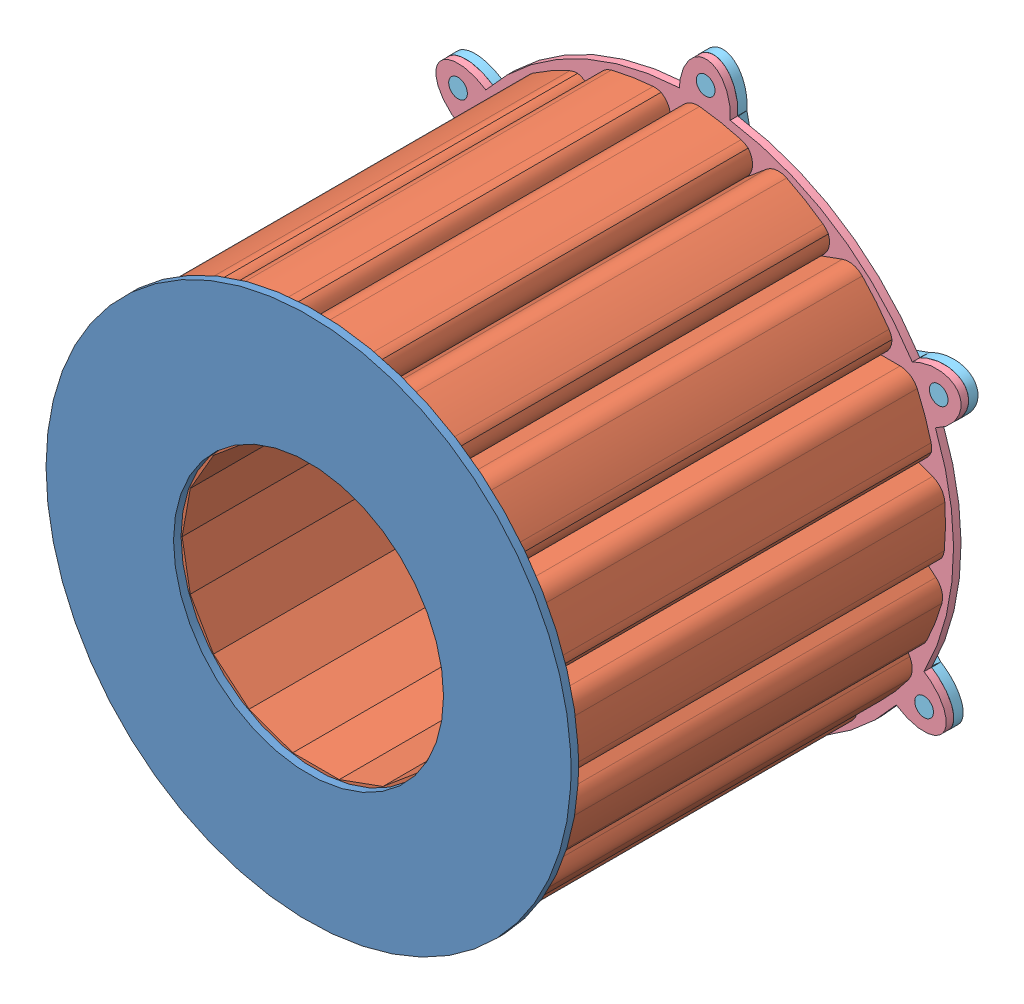
SolidWorks assembly Assem_limit_mates, configuration Default. Lengths in mm.
Overall size (206.65 197.8 119).
39 component instances, 5 part files, 12 mates.
Components (placement in the parent):
- Iris_Plate_2-1: Iris_Plate_2 [Default] at origin size (140 140 2)
- Iris_Leaflet-1: Iris_Leaflet [Default] at (-35.6931 0 -100) size (18.27 59.73 101)
- Leaflet_Knob-1: Leaflet_Knob [Default] at (-35.6931 42.5 -102) x (0.872539 -0.488544 0) z (0 0 1) size (4 4 4)
- Iris_Plate_1-1: Iris_Plate_1 [Default] at (0 0 -102) x (0.891088 0.453831 0) z (0 0 1) size (160.49 140.23 2)
- Iris_Leaflet-2: Iris_Leaflet [Default] at (-33.5406 -12.2078 -100) x (0.939693 0.34202 0) z (0 0 1) size (18.27 59.73 101)
- Iris_Leaflet-3: Iris_Leaflet [Default] at (-27.3425 -22.9431 -100) x (0.766044 0.642788 0) z (0 0 1) size (18.27 59.73 101)
- Iris_Leaflet-4: Iris_Leaflet [Default] at (-17.8466 -30.9112 -100) x (0.5 0.866025 0) z (0 0 1) size (18.27 59.73 101)
- Iris_Leaflet-5: Iris_Leaflet [Default] at (-6.198 -35.1509 -100) x (0.173648 0.984808 0) z (0 0 1) size (18.27 59.73 101)
- Iris_Leaflet-6: Iris_Leaflet [Default] at (6.198 -35.1509 -100) x (-0.173648 0.984808 0) z (0 0 1) size (18.27 59.73 101)
- Iris_Leaflet-7: Iris_Leaflet [Default] at (17.8466 -30.9112 -100) x (-0.5 0.866025 0) z (0 0 1) size (18.27 59.73 101)
- Iris_Leaflet-8: Iris_Leaflet [Default] at (27.3425 -22.9431 -100) x (-0.766044 0.642788 0) z (0 0 1) size (18.27 59.73 101)
- Iris_Leaflet-9: Iris_Leaflet [Default] at (33.5406 -12.2078 -100) x (-0.939693 0.34202 0) z (0 0 1) size (18.27 59.73 101)
- Iris_Leaflet-10: Iris_Leaflet [Default] at (35.6931 0 -100) x (-1 0 0) z (0 0 1) size (18.27 59.73 101)
- Iris_Leaflet-11: Iris_Leaflet [Default] at (33.5406 12.2078 -100) x (-0.939693 -0.34202 0) z (0 0 1) size (18.27 59.73 101)
- Iris_Leaflet-12: Iris_Leaflet [Default] at (27.3425 22.9431 -100) x (-0.766044 -0.642788 0) z (0 0 1) size (18.27 59.73 101)
- Iris_Leaflet-13: Iris_Leaflet [Default] at (17.8466 30.9112 -100) x (-0.5 -0.866025 0) z (0 0 1) size (18.27 59.73 101)
- Iris_Leaflet-14: Iris_Leaflet [Default] at (6.198 35.1509 -100) x (-0.173648 -0.984808 0) z (0 0 1) size (18.27 59.73 101)
- Iris_Leaflet-15: Iris_Leaflet [Default] at (-6.198 35.1509 -100) x (0.173648 -0.984808 0) z (0 0 1) size (18.27 59.73 101)
- Iris_Leaflet-16: Iris_Leaflet [Default] at (-17.8466 30.9112 -100) x (0.5 -0.866025 0) z (0 0 1) size (18.27 59.73 101)
- Iris_Leaflet-17: Iris_Leaflet [Default] at (-27.3425 22.9431 -100) x (0.766044 -0.642788 0) z (0 0 1) size (18.27 59.73 101)
- Iris_Leaflet-18: Iris_Leaflet [Default] at (-33.5406 12.2078 -100) x (0.939693 -0.34202 0) z (0 0 1) size (18.27 59.73 101)
- Motor_mount-1: Motor_mount [Default] at (0 0 -102) x (0.544789 0.838573 0) z (0 0 1) size (140.24 160.5 17)
- Leaflet_Knob-2: Leaflet_Knob [Default] at (-48.0764 27.7292 -102) x (0.987011 -0.160655 0) z (0 0 1) size (4 4 4)
- Leaflet_Knob-3: Leaflet_Knob [Default] at (-54.661 9.6138 -102) x (0.982434 0.186611 0) z (0 0 1) size (4 4 4)
- Leaflet_Knob-4: Leaflet_Knob [Default] at (-54.6526 -9.6612 -102) x (0.859361 0.511369 0) z (0 0 1) size (4 4 4)
- Leaflet_Knob-5: Leaflet_Knob [Default] at (-48.0524 -27.7708 -102) x (0.632637 0.774449 0) z (0 0 1) size (4 4 4)
- Leaflet_Knob-6: Leaflet_Knob [Default] at (-35.6563 -42.5309 -102) x (0.329607 0.944118 0) z (0 0 1) size (4 4 4)
- Leaflet_Knob-7: Leaflet_Knob [Default] at (-18.9595 -52.1612 -102) x (-0.013178 0.999913 0) z (0 0 1) size (4 4 4)
- Leaflet_Knob-8: Leaflet_Knob [Default] at (0.0241 -55.5 -102) x (-0.354374 0.935104 0) z (0 0 1) size (4 4 4)
- Leaflet_Knob-9: Leaflet_Knob [Default] at (19.0047 -52.1447 -102) x (-0.652827 0.757507 0) z (0 0 1) size (4 4 4)
- Leaflet_Knob-10: Leaflet_Knob [Default] at (35.6931 -42.5 -102) x (-0.872539 0.488544 0) z (0 0 1) size (4 4 4)
- Leaflet_Knob-11: Leaflet_Knob [Default] at (48.0764 -27.7292 -102) x (-0.987011 0.160655 0) z (0 0 1) size (4 4 4)
- Leaflet_Knob-12: Leaflet_Knob [Default] at (54.661 -9.6138 -102) x (-0.982434 -0.186611 0) z (0 0 1) size (4 4 4)
- Leaflet_Knob-13: Leaflet_Knob [Default] at (54.6526 9.6612 -102) x (-0.859361 -0.511369 0) z (0 0 1) size (4 4 4)
- Leaflet_Knob-14: Leaflet_Knob [Default] at (48.0524 27.7708 -102) x (-0.632637 -0.774449 0) z (0 0 1) size (4 4 4)
- Leaflet_Knob-15: Leaflet_Knob [Default] at (35.6563 42.5309 -102) x (-0.329607 -0.944118 0) z (0 0 1) size (4 4 4)
- Leaflet_Knob-16: Leaflet_Knob [Default] at (18.9595 52.1612 -102) x (0.013178 -0.999913 0) z (0 0 1) size (4 4 4)
- Leaflet_Knob-17: Leaflet_Knob [Default] at (-0.0241 55.5 -102) x (0.354374 -0.935104 0) z (0 0 1) size (4 4 4)
- Leaflet_Knob-18: Leaflet_Knob [Default] at (-19.0047 52.1447 -102) x (0.652827 -0.757507 0) z (0 0 1) size (4 4 4)
Mates (geometry in assembly coordinates):
- Coincident1: coincident anti-aligned: plane of Iris_Plate_2-1 through (0 0 0) normal (0 0 -1); plane of Iris_Leaflet-1 through (-35.6931 0 0) normal (0 0 1)
- Coincident2: coincident anti-aligned: plane of Iris_Plate_2-1 through (-41 39.5 1) normal (0 1 0); plane of Iris_Leaflet-1 through (-40.6931 39.5 1) normal (0 -1 0)
- LimitDistance1: limit distance = 32.6931 mm: cylinder of Iris_Plate_2-1 through (3 40 1) axis (0 0 -1) radius 0.5; point of Iris_Leaflet-1
- LimitDistance2: limit distance = 0.3069 mm: cylinder of Iris_Plate_2-1 through (-41 40 1) axis (0 0 -1) radius 0.5; point of Iris_Leaflet-1
- Concentric2: concentric aligned: cylinder of Iris_Leaflet-1 through (-35.6931 42.5 -98) axis (0 0 -1) radius 2; cylinder of Leaflet_Knob-1 through (-35.6931 42.5 -98) axis (0 0 -1) radius 2
- Coincident3: coincident anti-aligned: plane of Iris_Leaflet-1 through (-35.6931 42.5 -98) normal (0 0 -1); plane of Leaflet_Knob-1 through (-35.6931 42.5 -98) normal (0 0 1)
- Concentric3: concentric aligned: circle of Iris_Plate_2-1; circle of Iris_Plate_1-1
- Coincident5: coincident anti-aligned: plane of Iris_Leaflet-1 through (-35.6931 0 -100) normal (0 0 -1); plane of Iris_Plate_1-1 through (-62.3762 -31.7682 -100) normal (0 0 1)
- Concentric4: concentric aligned: cylinder of Iris_Plate_1-1 through (-62.1373 40.3683 -100) axis (0 0 -1) radius 2.5; cylinder of Motor_mount-1 through (-62.1373 40.3683 -100) axis (0 0 -1) radius 2.5
- Coincident6: coincident anti-aligned: plane of Iris_Plate_1-1 through (-62.3762 -31.7682 -102) normal (0 0 -1); plane of Motor_mount-1 through (-58.7001 38.1353 -102) normal (0 0 1)
- Concentric5: concentric aligned: cylinder of Iris_Plate_1-1 through (-66.0286 -33.6284 -100) axis (0 0 -1) radius 2.5; cylinder of Motor_mount-1 through (-66.0286 -33.6284 -100) axis (0 0 -1) radius 2.5
- Slot2: slot aligned: cylinder of Leaflet_Knob-1 through (-35.6931 42.5 -98) axis (0 0 -1) radius 2; cylinder of Iris_Plate_1-1 through (-39.1185 16.6131 -100) axis (0 0 -1) radius 2.05; cylinder of ? through (-39.0379 16.8015 -100) axis (0 0 -1) radius 2.05
